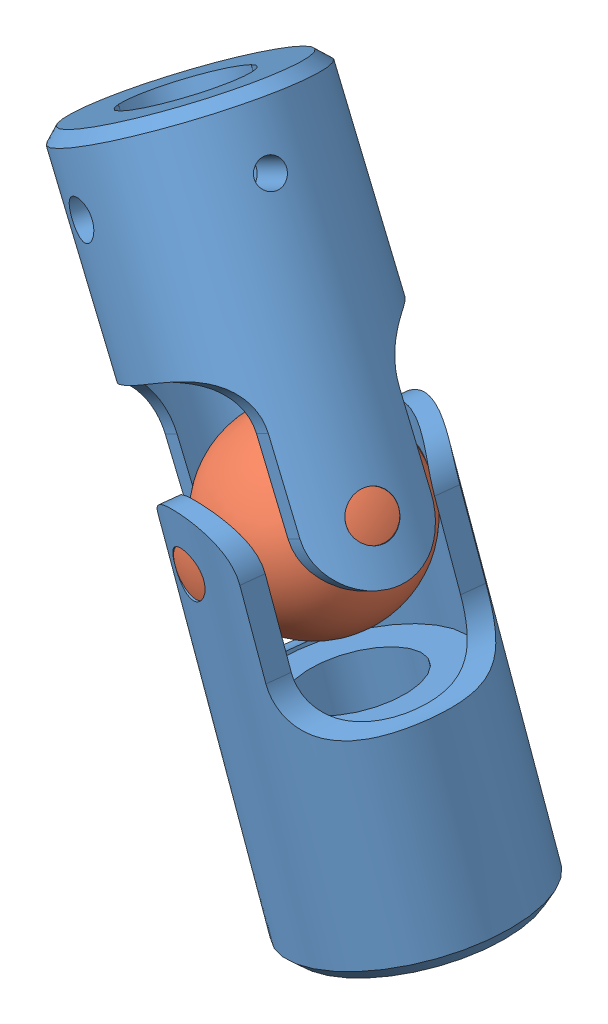
SolidWorks assembly ASSY_BERG_UJ3_U-JOINT_0250 SHAFT, configuration Default. Lengths in mm.
Overall size (29.79 40.34 17.97).
3 component instances, 2 part files, 7 mates.
Components (placement in the parent):
- UJ-3_YOKE-1: UJ-3_YOKE [Default] x (-0.29846 0.953854 0.032934) z (-0.926607 -0.281319 -0.249516) size (22.23 12.7 12.7)
- UJ-3_BALL-1: UJ-3_BALL [Default] x (-0.540507 0.840544 -0.036564) z (0.228737 0.104988 -0.96781) size (10.58 12.7 12.7)
- UJ-3_YOKE-3: UJ-3_YOKE [Default] x (0.519617 -0.846363 0.11691) z (-0.272888 -0.034734 0.961419) size (22.23 12.7 12.7)
Mates (geometry in assembly coordinates):
- Coincident11: coincident: point of UJ-3_BALL-1; plane of assembly
- Coincident12: coincident: point of UJ-3_BALL-1; plane of assembly
- Coincident13: coincident: point of UJ-3_BALL-1; plane of assembly
- Coincident14: coincident: point of UJ-3_YOKE-1; point of UJ-3_BALL-1
- Coincident15: coincident aligned: axis of UJ-3_YOKE-1 through (1.5311 0.7027 -6.4781) axis (-0.228737 -0.104988 0.96781); axis of UJ-3_BALL-1 through (1.6022 0.7354 -6.7793) axis (-0.228737 -0.104988 0.96781)
- Coincident16: coincident: point of UJ-3_BALL-1; point of UJ-3_YOKE-3
- Coincident17: coincident anti-aligned: axis of UJ-3_BALL-1 through (4.1592 2.7302 1.2792) axis (0.809649 0.531472 0.24901); axis of UJ-3_YOKE-3 through (5.4195 3.5575 1.6668) axis (-0.809649 -0.531472 -0.24901)
